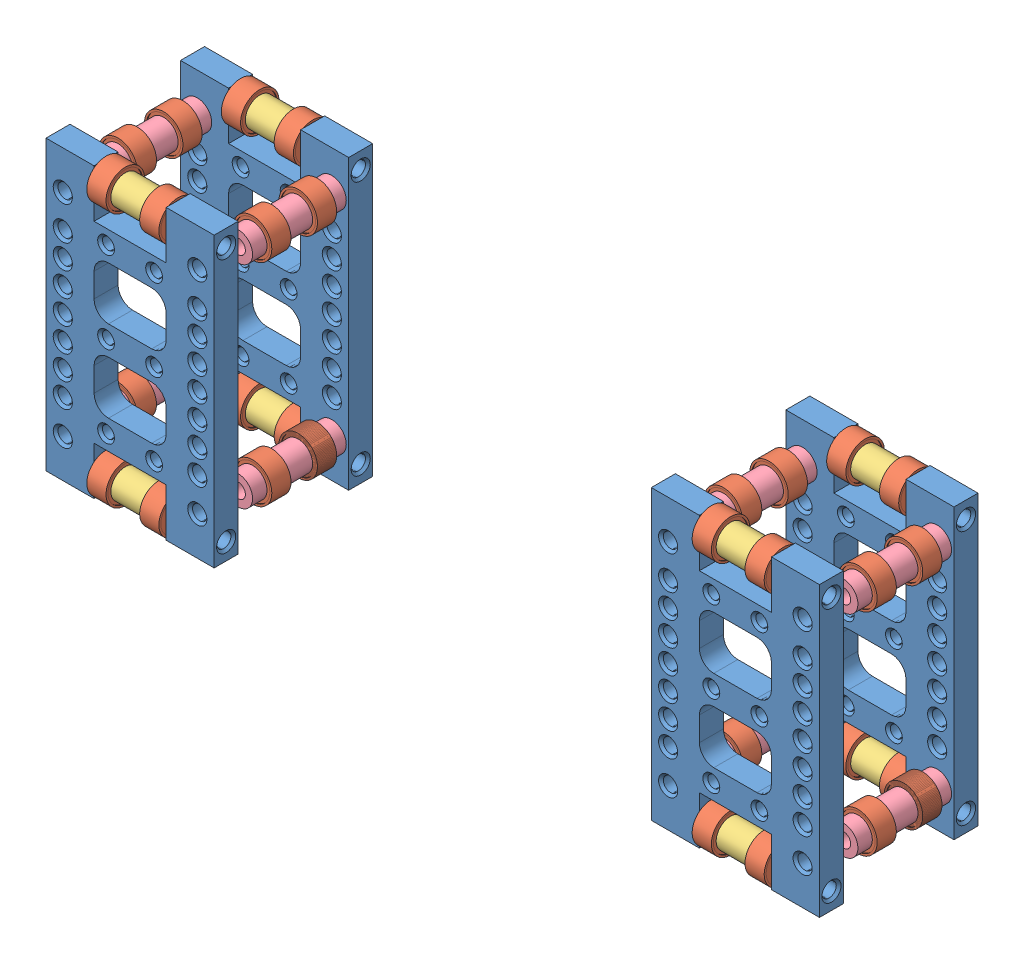
SolidWorks assembly 轴套连接, configuration 默认. Lengths in mm.
Overall size (165.3 64.3 37.71).
74 component instances, 4 part files, 3 mates.
Components (placement in the parent):
- 轴套-1: 轴套 [默认] at (116.3157 -25.342 112.0745) size (39.3 64.3 37.71)
  - 上层手20管轴承一侧总装06-10tang-最终版薄LG-A4-0613-2: 上层手20管轴承一侧总装06-10tang-最终版薄LG-A4-0613 [默认] at (-73.2578 28.4299 -27.5745) size (35 64.3 11.3) (flexible)
    - 上层手20管轴承套片06-10tang-最终版薄LG-A4-0613-1: 上层手20管轴承套片06-10tang-最终版薄LG-A4-0613 [默认] at origin size (35 60 5)
    - 3-8-4z轴承薄LG-A4-0613-1: 3-8-4z轴承薄LG-A4-0613 [默认] at (3.5 -26.5 2.5) x (0 -0.999951 0.00986) z (0 0.00986 0.999951) size (8 4 8)
    - 3-8-4z轴承薄LG-A4-0613-7: 3-8-4z轴承薄LG-A4-0613 [默认] at (-7.5 -26.5 2.5) x (0 -0.665537 0.746365) z (0 0.746365 0.665537) size (8 4 8)
    - 3-8-4z轴承薄LG-A4-0613-8: 3-8-4z轴承薄LG-A4-0613 [默认] at (3.5 26.5 2.5) x (0 -0.999951 0.00986) z (0 0.00986 0.999951) size (8 4 8)
    - 3-8-4z轴承薄LG-A4-0613-9: 3-8-4z轴承薄LG-A4-0613 [默认] at (-7.5 26.5 2.5) x (0 -0.665575 -0.746331) z (0 -0.746331 0.665575) size (8 4 8)
    - 套-1: 套 [默认] at (3.5 26.5 2.5) x (0 0.994477 -0.104954) z (0 0.104954 0.994477) size (6 7 6)
    - 套-2: 套 [默认] at (3.5 -26.5 2.5) x (0 0.746698 0.665163) z (0 -0.665163 0.746698) size (6 7 6)
  - 轴套06-10tang-最终版薄LG-A4-0613-3: 轴套06-10tang-最终版薄LG-A4-0613 [默认] at (-59.2578 6.4299 -6.0745) x (-0.391508 -0.920175 0) z (0 0 1) size (6 6 3)
  - 轴套06-10tang-最终版薄LG-A4-0613-5: 轴套06-10tang-最终版薄LG-A4-0613 [默认] at (-59.2578 6.4299 -22.5745) x (0.842894 -0.53808 0) z (0 0 1) size (6 6 3)
  - 3-8-4z轴承薄LG-A4-0613-18: 3-8-4z轴承薄LG-A4-0613 [默认] at (-59.2578 6.4299 -15.5745) x (0.420264 0.907402 0) z (-0.907402 0.420264 0) size (8 4 8)
  - 轴套06-10tang-最终版薄LG-A4-0613-22: 轴套06-10tang-最终版薄LG-A4-0613 [5.5] at (-59.2578 6.4299 -15.5745) x (0.649896 0.760023 0) z (0 0 1) size (6 6 5.5)
  - 3-8-4z轴承薄LG-A4-0613-25: 3-8-4z轴承薄LG-A4-0613 [默认] at (-59.2578 6.4299 -15.5745) x (0.746365 -0.665537 0) z (0.665537 0.746365 0) size (8 4 8)
  - 3-8-4z轴承薄LG-A4-0613-26: 3-8-4z轴承薄LG-A4-0613 [默认] at (-59.2578 6.4299 -6.0745) x (0.856729 -0.515766 0) z (0.515766 0.856729 0) size (8 4 8)
  - 轴套06-10tang-最终版薄LG-A4-0613-26: 轴套06-10tang-最终版薄LG-A4-0613 [默认] at (-87.2578 6.4299 -6.0745) x (-0.391508 -0.920175 0) z (0 0 1) size (6 6 3)
  - 轴套06-10tang-最终版薄LG-A4-0613-27: 轴套06-10tang-最终版薄LG-A4-0613 [默认] at (-59.2578 50.4299 -6.0745) x (-0.391508 -0.920175 0) z (0 0 1) size (6 6 3)
  - 轴套06-10tang-最终版薄LG-A4-0613-28: 轴套06-10tang-最终版薄LG-A4-0613 [默认] at (-87.2578 50.4299 -6.0745) x (-0.391508 -0.920175 0) z (0 0 1) size (6 6 3)
  - 3-8-4z轴承薄LG-A4-0613-27: 3-8-4z轴承薄LG-A4-0613 [默认] at (-87.2578 6.4299 -6.0745) x (0.856729 -0.515766 0) z (0.515766 0.856729 0) size (8 4 8)
  - 3-8-4z轴承薄LG-A4-0613-28: 3-8-4z轴承薄LG-A4-0613 [默认] at (-59.2578 50.4299 -6.0745) x (0.856729 -0.515766 0) z (0.515766 0.856729 0) size (8 4 8)
  - 3-8-4z轴承薄LG-A4-0613-29: 3-8-4z轴承薄LG-A4-0613 [默认] at (-87.2578 50.4299 -6.0745) x (0.856729 -0.515766 0) z (0.515766 0.856729 0) size (8 4 8)
  - 轴套06-10tang-最终版薄LG-A4-0613-29: 轴套06-10tang-最终版薄LG-A4-0613 [5.5] at (-87.2578 6.4299 -15.5745) x (0.649896 0.760023 0) z (0 0 1) size (6 6 5.5)
  - 轴套06-10tang-最终版薄LG-A4-0613-30: 轴套06-10tang-最终版薄LG-A4-0613 [5.5] at (-59.2578 50.4299 -15.5745) x (0.649896 0.760023 0) z (0 0 1) size (6 6 5.5)
  - 轴套06-10tang-最终版薄LG-A4-0613-31: 轴套06-10tang-最终版薄LG-A4-0613 [5.5] at (-87.2578 50.4299 -15.5745) x (0.649896 0.760023 0) z (0 0 1) size (6 6 5.5)
  - 3-8-4z轴承薄LG-A4-0613-30: 3-8-4z轴承薄LG-A4-0613 [默认] at (-87.2578 6.4299 -15.5745) x (0.746365 -0.665537 0) z (0.665537 0.746365 0) size (8 4 8)
  - 3-8-4z轴承薄LG-A4-0613-31: 3-8-4z轴承薄LG-A4-0613 [默认] at (-59.2578 50.4299 -15.5745) x (0.746365 -0.665537 0) z (0.665537 0.746365 0) size (8 4 8)
  - 3-8-4z轴承薄LG-A4-0613-32: 3-8-4z轴承薄LG-A4-0613 [默认] at (-87.2578 50.4299 -15.5745) x (0.746365 -0.665537 0) z (0.665537 0.746365 0) size (8 4 8)
  - 轴套06-10tang-最终版薄LG-A4-0613-32: 轴套06-10tang-最终版薄LG-A4-0613 [默认] at (-87.2578 6.4299 -22.5745) x (0.842894 -0.53808 0) z (0 0 1) size (6 6 3)
  - 轴套06-10tang-最终版薄LG-A4-0613-33: 轴套06-10tang-最终版薄LG-A4-0613 [默认] at (-59.2578 50.4299 -22.5745) x (0.842894 -0.53808 0) z (0 0 1) size (6 6 3)
  - 轴套06-10tang-最终版薄LG-A4-0613-34: 轴套06-10tang-最终版薄LG-A4-0613 [默认] at (-87.2578 50.4299 -22.5745) x (0.842894 -0.53808 0) z (0 0 1) size (6 6 3)
  - 上层手20管轴承套片06-10tang-最终版薄LG-A4-0613-1: 上层手20管轴承套片06-10tang-最终版薄LG-A4-0613 [默认] at (-73.2578 28.4299 0.4255) size (35 60 5)
  - 3-8-4z轴承薄LG-A4-0613-33: 3-8-4z轴承薄LG-A4-0613 [默认] at (-80.7578 54.9299 2.9255) x (0 -0.999879 0.015539) z (0 0.015539 0.999879) size (8 4 8)
  - 套-1: 套 [默认] at (-69.7578 54.9299 2.9255) x (0 0.975605 -0.219534) z (0 0.219534 0.975605) size (6 7 6)
  - 3-8-4z轴承薄LG-A4-0613-34: 3-8-4z轴承薄LG-A4-0613 [默认] at (-69.7578 54.9299 2.9255) x (0 -0.999951 0.00986) z (0 0.00986 0.999951) size (8 4 8)
  - 套-2: 套 [默认] at (-69.7578 1.9299 2.9255) x (0 0.975605 -0.219534) z (0 0.219534 0.975605) size (6 7 6)
  - 3-8-4z轴承薄LG-A4-0613-35: 3-8-4z轴承薄LG-A4-0613 [默认] at (-80.7578 1.9299 2.9255) x (0 -0.999879 0.015539) z (0 0.015539 0.999879) size (8 4 8)
  - 3-8-4z轴承薄LG-A4-0613-36: 3-8-4z轴承薄LG-A4-0613 [默认] at (-69.7578 1.9299 2.9255) x (0 -0.999951 0.00986) z (0 0.00986 0.999951) size (8 4 8)
- 轴套-2: 轴套 [默认] at (-9.6843 -25.342 112.0745) size (39.3 64.3 37.71)
  - 上层手20管轴承一侧总装06-10tang-最终版薄LG-A4-0613-2: 上层手20管轴承一侧总装06-10tang-最终版薄LG-A4-0613 [默认] at (-73.2578 28.4299 -27.5745) size (35 64.3 11.3) (flexible)
    - 上层手20管轴承套片06-10tang-最终版薄LG-A4-0613-1: 上层手20管轴承套片06-10tang-最终版薄LG-A4-0613 [默认] at origin size (35 60 5)
    - 3-8-4z轴承薄LG-A4-0613-1: 3-8-4z轴承薄LG-A4-0613 [默认] at (3.5 -26.5 2.5) x (0 -0.999951 0.00986) z (0 0.00986 0.999951) size (8 4 8)
    - 3-8-4z轴承薄LG-A4-0613-7: 3-8-4z轴承薄LG-A4-0613 [默认] at (-7.5 -26.5 2.5) x (0 -0.665537 0.746365) z (0 0.746365 0.665537) size (8 4 8)
    - 3-8-4z轴承薄LG-A4-0613-8: 3-8-4z轴承薄LG-A4-0613 [默认] at (3.5 26.5 2.5) x (0 -0.999951 0.00986) z (0 0.00986 0.999951) size (8 4 8)
    - 3-8-4z轴承薄LG-A4-0613-9: 3-8-4z轴承薄LG-A4-0613 [默认] at (-7.5 26.5 2.5) x (0 -0.665575 -0.746331) z (0 -0.746331 0.665575) size (8 4 8)
    - 套-1: 套 [默认] at (3.5 26.5 2.5) x (0 0.994477 -0.104954) z (0 0.104954 0.994477) size (6 7 6)
    - 套-2: 套 [默认] at (3.5 -26.5 2.5) x (0 0.746698 0.665163) z (0 -0.665163 0.746698) size (6 7 6)
  - 轴套06-10tang-最终版薄LG-A4-0613-3: 轴套06-10tang-最终版薄LG-A4-0613 [默认] at (-59.2578 6.4299 -6.0745) x (-0.391508 -0.920175 0) z (0 0 1) size (6 6 3)
  - 轴套06-10tang-最终版薄LG-A4-0613-5: 轴套06-10tang-最终版薄LG-A4-0613 [默认] at (-59.2578 6.4299 -22.5745) x (0.842894 -0.53808 0) z (0 0 1) size (6 6 3)
  - 3-8-4z轴承薄LG-A4-0613-18: 3-8-4z轴承薄LG-A4-0613 [默认] at (-59.2578 6.4299 -15.5745) x (0.420264 0.907402 0) z (-0.907402 0.420264 0) size (8 4 8)
  - 轴套06-10tang-最终版薄LG-A4-0613-22: 轴套06-10tang-最终版薄LG-A4-0613 [5.5] at (-59.2578 6.4299 -15.5745) x (0.649896 0.760023 0) z (0 0 1) size (6 6 5.5)
  - 3-8-4z轴承薄LG-A4-0613-25: 3-8-4z轴承薄LG-A4-0613 [默认] at (-59.2578 6.4299 -15.5745) x (0.746365 -0.665537 0) z (0.665537 0.746365 0) size (8 4 8)
  - 3-8-4z轴承薄LG-A4-0613-26: 3-8-4z轴承薄LG-A4-0613 [默认] at (-59.2578 6.4299 -6.0745) x (0.856729 -0.515766 0) z (0.515766 0.856729 0) size (8 4 8)
  - 轴套06-10tang-最终版薄LG-A4-0613-26: 轴套06-10tang-最终版薄LG-A4-0613 [默认] at (-87.2578 6.4299 -6.0745) x (-0.391508 -0.920175 0) z (0 0 1) size (6 6 3)
  - 轴套06-10tang-最终版薄LG-A4-0613-27: 轴套06-10tang-最终版薄LG-A4-0613 [默认] at (-59.2578 50.4299 -6.0745) x (-0.391508 -0.920175 0) z (0 0 1) size (6 6 3)
  - 轴套06-10tang-最终版薄LG-A4-0613-28: 轴套06-10tang-最终版薄LG-A4-0613 [默认] at (-87.2578 50.4299 -6.0745) x (-0.391508 -0.920175 0) z (0 0 1) size (6 6 3)
  - 3-8-4z轴承薄LG-A4-0613-27: 3-8-4z轴承薄LG-A4-0613 [默认] at (-87.2578 6.4299 -6.0745) x (0.856729 -0.515766 0) z (0.515766 0.856729 0) size (8 4 8)
  - 3-8-4z轴承薄LG-A4-0613-28: 3-8-4z轴承薄LG-A4-0613 [默认] at (-59.2578 50.4299 -6.0745) x (0.856729 -0.515766 0) z (0.515766 0.856729 0) size (8 4 8)
  - 3-8-4z轴承薄LG-A4-0613-29: 3-8-4z轴承薄LG-A4-0613 [默认] at (-87.2578 50.4299 -6.0745) x (0.856729 -0.515766 0) z (0.515766 0.856729 0) size (8 4 8)
  - 轴套06-10tang-最终版薄LG-A4-0613-29: 轴套06-10tang-最终版薄LG-A4-0613 [5.5] at (-87.2578 6.4299 -15.5745) x (0.649896 0.760023 0) z (0 0 1) size (6 6 5.5)
  - 轴套06-10tang-最终版薄LG-A4-0613-30: 轴套06-10tang-最终版薄LG-A4-0613 [5.5] at (-59.2578 50.4299 -15.5745) x (0.649896 0.760023 0) z (0 0 1) size (6 6 5.5)
  - 轴套06-10tang-最终版薄LG-A4-0613-31: 轴套06-10tang-最终版薄LG-A4-0613 [5.5] at (-87.2578 50.4299 -15.5745) x (0.649896 0.760023 0) z (0 0 1) size (6 6 5.5)
  - 3-8-4z轴承薄LG-A4-0613-30: 3-8-4z轴承薄LG-A4-0613 [默认] at (-87.2578 6.4299 -15.5745) x (0.746365 -0.665537 0) z (0.665537 0.746365 0) size (8 4 8)
  - 3-8-4z轴承薄LG-A4-0613-31: 3-8-4z轴承薄LG-A4-0613 [默认] at (-59.2578 50.4299 -15.5745) x (0.746365 -0.665537 0) z (0.665537 0.746365 0) size (8 4 8)
  - 3-8-4z轴承薄LG-A4-0613-32: 3-8-4z轴承薄LG-A4-0613 [默认] at (-87.2578 50.4299 -15.5745) x (0.746365 -0.665537 0) z (0.665537 0.746365 0) size (8 4 8)
  - 轴套06-10tang-最终版薄LG-A4-0613-32: 轴套06-10tang-最终版薄LG-A4-0613 [默认] at (-87.2578 6.4299 -22.5745) x (0.842894 -0.53808 0) z (0 0 1) size (6 6 3)
  - 轴套06-10tang-最终版薄LG-A4-0613-33: 轴套06-10tang-最终版薄LG-A4-0613 [默认] at (-59.2578 50.4299 -22.5745) x (0.842894 -0.53808 0) z (0 0 1) size (6 6 3)
  - 轴套06-10tang-最终版薄LG-A4-0613-34: 轴套06-10tang-最终版薄LG-A4-0613 [默认] at (-87.2578 50.4299 -22.5745) x (0.842894 -0.53808 0) z (0 0 1) size (6 6 3)
  - 上层手20管轴承套片06-10tang-最终版薄LG-A4-0613-1: 上层手20管轴承套片06-10tang-最终版薄LG-A4-0613 [默认] at (-73.2578 28.4299 0.4255) size (35 60 5)
  - 3-8-4z轴承薄LG-A4-0613-33: 3-8-4z轴承薄LG-A4-0613 [默认] at (-80.7578 54.9299 2.9255) x (0 -0.999879 0.015539) z (0 0.015539 0.999879) size (8 4 8)
  - 套-1: 套 [默认] at (-69.7578 54.9299 2.9255) x (0 0.975605 -0.219534) z (0 0.219534 0.975605) size (6 7 6)
  - 3-8-4z轴承薄LG-A4-0613-34: 3-8-4z轴承薄LG-A4-0613 [默认] at (-69.7578 54.9299 2.9255) x (0 -0.999951 0.00986) z (0 0.00986 0.999951) size (8 4 8)
  - 套-2: 套 [默认] at (-69.7578 1.9299 2.9255) x (0 0.975605 -0.219534) z (0 0.219534 0.975605) size (6 7 6)
  - 3-8-4z轴承薄LG-A4-0613-35: 3-8-4z轴承薄LG-A4-0613 [默认] at (-80.7578 1.9299 2.9255) x (0 -0.999879 0.015539) z (0 0.015539 0.999879) size (8 4 8)
  - 3-8-4z轴承薄LG-A4-0613-36: 3-8-4z轴承薄LG-A4-0613 [默认] at (-69.7578 1.9299 2.9255) x (0 -0.999951 0.00986) z (0 0.00986 0.999951) size (8 4 8)
Mates (geometry in assembly coordinates):
- 距离1: distance = 91 mm: plane of 轴套-1/上层手20管轴承一侧总装06-10tang-最终版薄LG-A4-0613-2/上层手20管轴承套片06-10tang-最终版薄LG-A4-0613-1 through (25.5579 -26.9122 89.5) normal (-1 0 0); plane of 轴套-2/上层手20管轴承套片06-10tang-最终版薄LG-A4-0613-1 through (-65.4421 -26.9122 117.5) normal (1 0 0)
- 重合2: coincident: plane of 轴套-1/上层手20管轴承套片06-10tang-最终版薄LG-A4-0613-1 through (25.5579 33.0878 117.5) normal (0 1 0); plane of 轴套-2/上层手20管轴承套片06-10tang-最终版薄LG-A4-0613-1 through (-100.4421 33.0878 117.5) normal (0 1 0)
- 重合3: coincident: plane of 轴套-1/上层手20管轴承一侧总装06-10tang-最终版薄LG-A4-0613-2/上层手20管轴承套片06-10tang-最终版薄LG-A4-0613-1 through (60.5579 33.0878 84.5) normal (0 0 -1); plane of 轴套-2/上层手20管轴承一侧总装06-10tang-最终版薄LG-A4-0613-2/上层手20管轴承套片06-10tang-最终版薄LG-A4-0613-1 through (-65.4421 33.0878 84.5) normal (0 0 -1)
